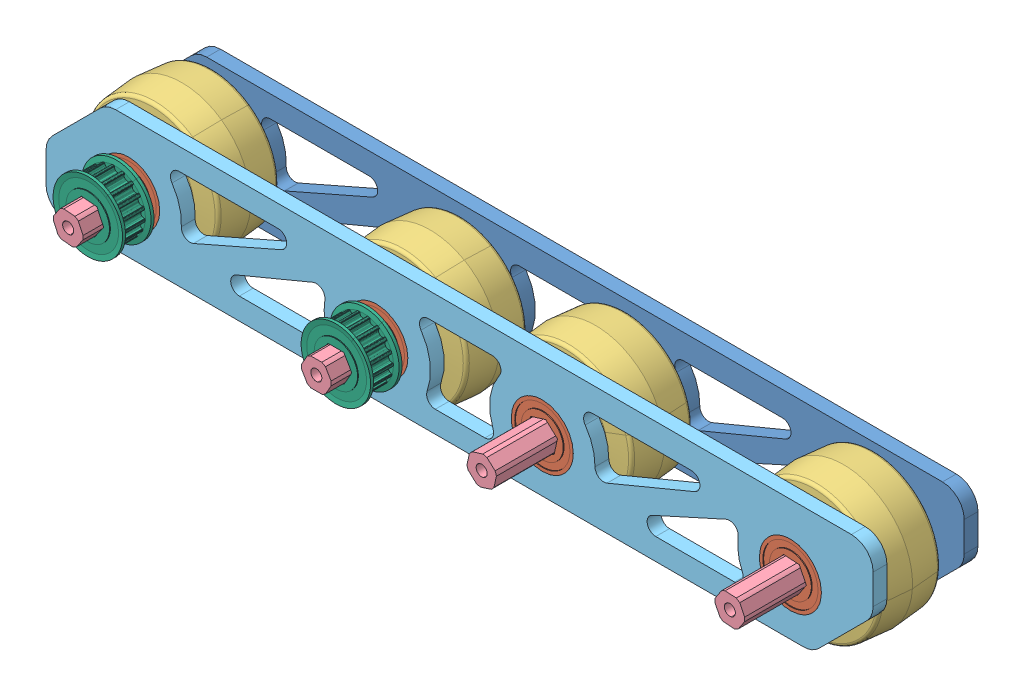
SolidWorks assembly 8WD, configuration Default. Lengths in mm.
Overall size (387.11 89.13 76.2).
20 component instances, 6 part files, 48 mates.
Components (placement in the parent):
- Part1-1: Part1 [Default] at (-97.1062 261.1901 376.3689) size (381 55.88 6.35)
- 0_500_Hex_ID_x_1_125_OD_x_0_313_WD_Flanged_Bearing_v2_217-3875 (1).step-1: 0_500_Hex_ID_x_1_125_OD_x_0_313_WD_Flanged_Bearing_v2_217-3875 (1).step [Default] at (-59.0062 286.9076 376.3689) x (0.574007 0.818851 0) z (0.818851 -0.574007 0) size (31.12 7.94 31.12)
- 0_500_Hex_ID_x_1_125_OD_x_0_313_WD_Flanged_Bearing_v2_217-3875 (1).step-2: 0_500_Hex_ID_x_1_125_OD_x_0_313_WD_Flanged_Bearing_v2_217-3875 (1).step [Default] at (55.2938 285.3201 376.3689) x (-0.99999 -0.004566 0) z (-0.004566 0.99999 0) size (31.12 7.94 31.12)
- 0_500_Hex_ID_x_1_125_OD_x_0_313_WD_Flanged_Bearing_v2_217-3875 (1).step-3: 0_500_Hex_ID_x_1_125_OD_x_0_313_WD_Flanged_Bearing_v2_217-3875 (1).step [Default] at (131.4938 285.3201 376.3689) x (0.953429 0.301619 0) z (0.301619 -0.953429 0) size (31.12 7.94 31.12)
- 0_500_Hex_ID_x_1_125_OD_x_0_313_WD_Flanged_Bearing_v2_217-3875 (1).step-4: 0_500_Hex_ID_x_1_125_OD_x_0_313_WD_Flanged_Bearing_v2_217-3875 (1).step [Default] at (245.7938 286.9076 376.3689) x (0.99802 -0.062897 0) z (-0.062897 -0.99802 0) size (31.12 7.94 31.12)
- Colson_Performa_2_5_x_1_25_1_2_Hex_bore_217-4046.step-1: Colson_Performa_2_5_x_1_25_1_2_Hex_bore_217-4046.step [Default] at (245.7924 286.9104 400.1814) x (0 0 1) z (-0.99802 0.062897 0) size (33.1 63.5 63.5)
- ThunderHex.5 2.25in-1: ThunderHex.5 2.25in [Default] at (245.784 286.8928 604.9689) x (0.55348 0.832862 0) z (0 0 1) size (13.74 12.75 76.2)
- ThunderHex.5 2.25in-2: ThunderHex.5 2.25in [Default] at (131.4769 285.3147 604.9689) x (0.215505 0.976503 0) z (0 0 1) size (13.74 12.75 76.2)
- Colson_Performa_2_5_x_1_25_1_2_Hex_bore_217-4046.step-2: Colson_Performa_2_5_x_1_25_1_2_Hex_bore_217-4046.step [Default] at (131.4629 285.3103 400.1814) x (0 0 1) z (-0.953429 -0.301619 0) size (33.1 63.5 63.5)
- ThunderHex.5 2.25in-3: ThunderHex.5 2.25in [Default] at (55.3116 285.3202 604.9689) x (-0.503949 0.863733 0) z (0 0 1) size (13.74 12.75 76.2)
- Colson_Performa_2_5_x_1_25_1_2_Hex_bore_217-4046.step-3: Colson_Performa_2_5_x_1_25_1_2_Hex_bore_217-4046.step [Default] at (55.3043 285.3074 400.1814) x (0 0 1) z (-0.49604 -0.8683 0) size (33.1 63.5 63.5)
- ThunderHex.5 2.25in-4: ThunderHex.5 2.25in [Default] at (-58.9885 286.906 604.9689) x (-0.422142 0.90653 0) z (0 0 1) size (13.74 12.75 76.2)
- Colson_Performa_2_5_x_1_25_1_2_Hex_bore_217-4046.step-4: Colson_Performa_2_5_x_1_25_1_2_Hex_bore_217-4046.step [Default] at (-58.9969 286.894 400.1814) x (0 0 1) z (-0.574007 -0.818851 0) size (33.1 63.5 63.5)
- Part2-1: Part2 [Default] at (-97.1062 261.1901 418.3186) size (381 55.88 6.35)
- 0_500_Hex_ID_x_1_125_OD_x_0_313_WD_Flanged_Bearing_v2_217-3875 (1).step-8: 0_500_Hex_ID_x_1_125_OD_x_0_313_WD_Flanged_Bearing_v2_217-3875 (1).step [Default] at (55.2938 285.3201 424.6686) x (-0.99999 -0.004566 0) z (0.004566 -0.99999 0) size (31.12 7.94 31.12)
- 0_500_Hex_ID_x_1_125_OD_x_0_313_WD_Flanged_Bearing_v2_217-3875 (1).step-6: 0_500_Hex_ID_x_1_125_OD_x_0_313_WD_Flanged_Bearing_v2_217-3875 (1).step [Default] at (131.4938 285.3201 424.6686) x (0.953429 0.301619 0) z (-0.301619 0.953429 0) size (31.12 7.94 31.12)
- 0_500_Hex_ID_x_1_125_OD_x_0_313_WD_Flanged_Bearing_v2_217-3875 (1).step-5: 0_500_Hex_ID_x_1_125_OD_x_0_313_WD_Flanged_Bearing_v2_217-3875 (1).step [Default] at (245.7938 286.9076 424.6686) x (0.99802 -0.062897 0) z (0.062897 0.99802 0) size (31.12 7.94 31.12)
- 0_500_Hex_ID_x_1_125_OD_x_0_313_WD_Flanged_Bearing_v2_217-3875 (1).step-7: 0_500_Hex_ID_x_1_125_OD_x_0_313_WD_Flanged_Bearing_v2_217-3875 (1).step [Default] at (-59.0062 286.9076 424.6686) x (0.574007 0.818851 0) z (-0.818851 0.574007 0) size (31.12 7.94 31.12)
- 18t_x_9mm_Wide_Double_Flange_Aluminum_Pulley_HTD_5mm_1_2_Hex_Bore_217-3225.step-1: 18t_x_9mm_Wide_Double_Flange_Aluminum_Pulley_HTD_5mm_1_2_Hex_Bore_217-3225.step [Default] at (-58.9592 286.9035 436.3044) x (0.574007 0.818851 0) z (0 0 1) size (32 32 14.5)
- 18t_x_9mm_Wide_Double_Flange_Aluminum_Pulley_HTD_5mm_1_2_Hex_Bore_217-3225.step-2: 18t_x_9mm_Wide_Double_Flange_Aluminum_Pulley_HTD_5mm_1_2_Hex_Bore_217-3225.step [Default] at (55.2971 285.2947 436.3044) x (0.49604 0.8683 0) z (0 0 1) size (32 32 14.5)
Mates (geometry in assembly coordinates):
- Concentric1: concentric: cylinder of Part1-1 through (-59.0062 286.9076 382.7189) axis (0 0 -1) radius 14.2875; cylinder of 0_500_Hex_ID_x_1_125_OD_x_0_313_WD_Flanged_Bearing_v2_217-3875 (1).step-1 through (-59.0062 286.9076 376.3689) axis (0 0 1) radius 14.2748
- Coincident1: coincident: plane of Part1-1 through (-97.1062 261.1901 382.7189) normal (0 0 1); plane of 0_500_Hex_ID_x_1_125_OD_x_0_313_WD_Flanged_Bearing_v2_217-3875 (1).step-1 through (-50.0761 299.6469 382.7189) normal (0 0 -1)
- Concentric2: concentric: cylinder of Part1-1 through (55.2938 285.3201 382.7189) axis (0 0 -1) radius 14.2875; cylinder of 0_500_Hex_ID_x_1_125_OD_x_0_313_WD_Flanged_Bearing_v2_217-3875 (1).step-2 through (55.2938 285.3201 376.3689) axis (0 0 1) radius 14.2748
- Concentric3: concentric: cylinder of Part1-1 through (131.4938 285.3201 382.7189) axis (0 0 -1) radius 14.2875; cylinder of 0_500_Hex_ID_x_1_125_OD_x_0_313_WD_Flanged_Bearing_v2_217-3875 (1).step-3 through (131.4938 285.3201 376.3689) axis (0 0 1) radius 14.2748
- Concentric4: concentric: cylinder of Part1-1 through (245.7938 286.9076 382.7189) axis (0 0 -1) radius 14.2875; cylinder of 0_500_Hex_ID_x_1_125_OD_x_0_313_WD_Flanged_Bearing_v2_217-3875 (1).step-4 through (245.7938 286.9076 376.3689) axis (0 0 1) radius 14.2748
- Coincident2: coincident: plane of Part1-1 through (-97.1062 261.1901 382.7189) normal (0 0 1); plane of 0_500_Hex_ID_x_1_125_OD_x_0_313_WD_Flanged_Bearing_v2_217-3875 (1).step-4 through (261.3205 285.9291 382.7189) normal (0 0 -1)
- Coincident3: coincident: plane of Part1-1 through (-97.1062 261.1901 382.7189) normal (0 0 1); plane of 0_500_Hex_ID_x_1_125_OD_x_0_313_WD_Flanged_Bearing_v2_217-3875 (1).step-3 through (146.3268 290.0125 382.7189) normal (0 0 -1)
- Coincident5: coincident: plane of Part1-1 through (-97.1062 261.1901 382.7189) normal (0 0 1); plane of 0_500_Hex_ID_x_1_125_OD_x_0_313_WD_Flanged_Bearing_v2_217-3875 (1).step-2 through (39.7365 285.2491 382.7189) normal (0 0 -1)
- Coincident7: coincident: plane of 0_500_Hex_ID_x_1_125_OD_x_0_313_WD_Flanged_Bearing_v2_217-3875 (1).step-4 through (241.7291 280.7911 376.3689) normal (0.062897 0.99802 0); plane of Colson_Performa_2_5_x_1_25_1_2_Hex_bore_217-4046.step-1 through (249.0512 280.3297 383.9318) normal (0.062897 0.99802 0)
- Coincident8: coincident: plane of 0_500_Hex_ID_x_1_125_OD_x_0_313_WD_Flanged_Bearing_v2_217-3875 (1).step-4 through (249.0585 280.3292 376.3689) normal (-0.832862 0.55348 0); plane of Colson_Performa_2_5_x_1_25_1_2_Hex_bore_217-4046.step-1 through (253.1208 286.4422 383.9318) normal (-0.832862 0.55348 0)
- Coincident9: coincident: plane of 0_500_Hex_ID_x_1_125_OD_x_0_313_WD_Flanged_Bearing_v2_217-3875 (1).step-4 through (249.8585 293.0241 376.3689) normal (-0.062897 -0.99802 0); plane of ThunderHex.5 2.25in-1 through (249.8585 293.0241 833.5689) normal (0.062897 0.99802 0)
- Coincident10: coincident: plane of 0_500_Hex_ID_x_1_125_OD_x_0_313_WD_Flanged_Bearing_v2_217-3875 (1).step-4 through (253.1232 286.4457 376.3689) normal (-0.895759 -0.44454 0); plane of ThunderHex.5 2.25in-1 through (253.1311 286.4298 833.5689) normal (0.895759 0.44454 0)
- Coincident11: coincident: plane of Part1-1 through (-97.1062 261.1901 376.3689) normal (0 0 -1); plane of ThunderHex.5 2.25in-1 through (245.784 286.8928 376.3689) normal (0 0 -1)
- Coincident12: coincident: plane of ThunderHex.5 2.25in-2 through (126.0445 290.283 833.5689) normal (-0.976503 0.215505 0); plane of Colson_Performa_2_5_x_1_25_1_2_Hex_bore_217-4046.step-2 through (124.4596 283.1015 383.9318) normal (0.976503 -0.215505 0)
- Coincident13: coincident: plane of ThunderHex.5 2.25in-2 through (124.458 283.0943 833.5689) normal (-0.674884 -0.737924 0); plane of Colson_Performa_2_5_x_1_25_1_2_Hex_bore_217-4046.step-2 through (129.8742 278.1409 383.9318) normal (0.674884 0.737924 0)
- Coincident15: coincident: plane of 0_500_Hex_ID_x_1_125_OD_x_0_313_WD_Flanged_Bearing_v2_217-3875 (1).step-3 through (138.4957 287.5352 376.3689) normal (-0.674884 -0.737924 0); plane of ThunderHex.5 2.25in-2 through (138.4957 287.5352 833.5689) normal (0.674884 0.737924 0)
- Coincident16: coincident: plane of 0_500_Hex_ID_x_1_125_OD_x_0_313_WD_Flanged_Bearing_v2_217-3875 (1).step-3 through (136.9131 280.3638 376.3689) normal (-0.976503 0.215505 0); plane of ThunderHex.5 2.25in-2 through (136.9092 280.3465 833.5689) normal (0.976503 -0.215505 0)
- Coincident17: coincident: plane of Part1-1 through (-97.1062 261.1901 376.3689) normal (0 0 -1); plane of ThunderHex.5 2.25in-2 through (131.4769 285.3147 376.3689) normal (0 0 -1)
- Coincident18: coincident: plane of ThunderHex.5 2.25in-3 through (47.95 285.2866 833.5689) normal (-0.863733 -0.503949 0); plane of Colson_Performa_2_5_x_1_25_1_2_Hex_bore_217-4046.step-3 through (51.6562 278.9344 383.9318) normal (0.863733 0.503949 0)
- Coincident19: coincident: plane of ThunderHex.5 2.25in-3 through (51.6599 278.928 833.5689) normal (0.004566 -0.99999 0); plane of Colson_Performa_2_5_x_1_25_1_2_Hex_bore_217-4046.step-3 through (58.9995 278.9616 383.9318) normal (-0.004566 0.99999 0)
- Coincident20: coincident: plane of ThunderHex.5 2.25in-4 through (-66.3218 287.5515 833.5689) normal (-0.90653 -0.422142 0); plane of Colson_Performa_2_5_x_1_25_1_2_Hex_bore_217-4046.step-4 through (-63.2172 280.8846 383.9318) normal (0.90653 0.422142 0)
- Coincident21: coincident: plane of ThunderHex.5 2.25in-4 through (-63.2141 280.8779 833.5689) normal (-0.087679 -0.996149 0); plane of Colson_Performa_2_5_x_1_25_1_2_Hex_bore_217-4046.step-4 through (-55.9027 280.2344 383.9318) normal (0.087679 0.996149 0)
- Coincident22: coincident: plane of 0_500_Hex_ID_x_1_125_OD_x_0_313_WD_Flanged_Bearing_v2_217-3875 (1).step-2 through (51.5929 291.6633 376.3689) normal (0.8683 -0.49604 0); plane of ThunderHex.5 2.25in-3 through (51.6017 291.6787 833.5689) normal (-0.8683 0.49604 0)
- Coincident23: coincident: plane of 0_500_Hex_ID_x_1_125_OD_x_0_313_WD_Flanged_Bearing_v2_217-3875 (1).step-2 through (47.95 285.2866 376.3689) normal (0.863733 0.503949 0); plane of ThunderHex.5 2.25in-3 through (47.95 285.2866 833.5689) normal (-0.863733 -0.503949 0)
- Coincident24: coincident: plane of 0_500_Hex_ID_x_1_125_OD_x_0_313_WD_Flanged_Bearing_v2_217-3875 (1).step-1 through (-62.1063 293.5651 376.3689) normal (0.818851 -0.574007 0); plane of ThunderHex.5 2.25in-4 through (-62.0961 293.5796 833.5689) normal (-0.818851 0.574007 0)
- Coincident25: coincident: plane of 0_500_Hex_ID_x_1_125_OD_x_0_313_WD_Flanged_Bearing_v2_217-3875 (1).step-1 through (-66.3218 287.5515 376.3689) normal (0.90653 0.422142 0); plane of ThunderHex.5 2.25in-4 through (-66.3218 287.5515 833.5689) normal (-0.90653 -0.422142 0)
- Coincident26: coincident: plane of Part1-1 through (-97.1062 261.1901 376.3689) normal (0 0 -1); plane of ThunderHex.5 2.25in-3 through (55.3116 285.3202 376.3689) normal (0 0 -1)
- Coincident27: coincident: plane of Part1-1 through (-97.1062 261.1901 376.3689) normal (0 0 -1); plane of ThunderHex.5 2.25in-4 through (-58.9885 286.906 376.3689) normal (0 0 -1)
- Coincident28: coincident: plane of Colson_Performa_2_5_x_1_25_1_2_Hex_bore_217-4046.step-3 through (40.0865 294.0011 416.0564) normal (0 0 1); plane of Colson_Performa_2_5_x_1_25_1_2_Hex_bore_217-4046.step-2 through (126.1767 302.0201 416.0564) normal (0 0 1)
- Coincident29: coincident: plane of Colson_Performa_2_5_x_1_25_1_2_Hex_bore_217-4046.step-3 through (40.0865 294.0011 416.0564) normal (0 0 1); plane of Colson_Performa_2_5_x_1_25_1_2_Hex_bore_217-4046.step-4 through (-73.3481 296.9541 416.0564) normal (0 0 1)
- Coincident30: coincident: plane of Colson_Performa_2_5_x_1_25_1_2_Hex_bore_217-4046.step-1 through (246.8948 304.4017 416.0564) normal (0 0 1); plane of Colson_Performa_2_5_x_1_25_1_2_Hex_bore_217-4046.step-2 through (126.1767 302.0201 416.0564) normal (0 0 1)
- Coincident31: coincident: plane of 0_500_Hex_ID_x_1_125_OD_x_0_313_WD_Flanged_Bearing_v2_217-3875 (1).step-1 through (-51.7163 297.307 384.3064) normal (0 0 1); plane of Colson_Performa_2_5_x_1_25_1_2_Hex_bore_217-4046.step-4 through (-73.3481 296.9541 384.3064) normal (0 0 -1)
- Coincident33: coincident: plane of ThunderHex.5 2.25in-4 through (-51.6551 286.2606 833.5689) normal (0.90653 0.422142 0); plane of 18t_x_9mm_Wide_Double_Flange_Aluminum_Pulley_HTD_5mm_1_2_Hex_Bore_217-3225.step-1 through (-53.2028 289.5841 443.5544) normal (-0.90653 -0.422142 0)
- Coincident34: coincident: plane of ThunderHex.5 2.25in-4 through (-55.8808 280.2325 833.5689) normal (0.818851 -0.574007 0); plane of 18t_x_9mm_Wide_Double_Flange_Aluminum_Pulley_HTD_5mm_1_2_Hex_Bore_217-3225.step-1 through (-53.7595 283.2585 443.5544) normal (-0.818851 0.574007 0)
- Coincident35: coincident: plane of ThunderHex.5 2.25in-3 through (51.6599 278.928 833.5689) normal (0.004566 -0.99999 0); plane of 18t_x_9mm_Wide_Double_Flange_Aluminum_Pulley_HTD_5mm_1_2_Hex_Bore_217-3225.step-2 through (55.3261 278.9448 443.5544) normal (-0.004566 0.99999 0)
- Coincident36: coincident: plane of ThunderHex.5 2.25in-3 through (47.95 285.2866 833.5689) normal (-0.863733 -0.503949 0); plane of 18t_x_9mm_Wide_Double_Flange_Aluminum_Pulley_HTD_5mm_1_2_Hex_Bore_217-3225.step-2 through (49.8124 282.0946 443.5544) normal (0.863733 0.503949 0)
- Coincident37: coincident: plane of 18t_x_9mm_Wide_Double_Flange_Aluminum_Pulley_HTD_5mm_1_2_Hex_Bore_217-3225.step-1 through (-58.9592 286.9035 443.5544) normal (0 0 1); plane of 18t_x_9mm_Wide_Double_Flange_Aluminum_Pulley_HTD_5mm_1_2_Hex_Bore_217-3225.step-2 through (55.2971 285.2947 443.5544) normal (0 0 1)
- Concentric9: concentric: cylinder of Part2-1 through (-59.0062 286.9076 424.6686) axis (0 0 -1) radius 14.2875; cylinder of 0_500_Hex_ID_x_1_125_OD_x_0_313_WD_Flanged_Bearing_v2_217-3875 (1).step-7 through (-59.0062 286.9076 424.6686) axis (0 0 -1) radius 14.2748
- Coincident42: coincident: plane of Part2-1 through (-97.1062 261.1901 418.3186) normal (0 0 -1); plane of 0_500_Hex_ID_x_1_125_OD_x_0_313_WD_Flanged_Bearing_v2_217-3875 (1).step-7 through (-50.0761 299.6469 418.3186) normal (0 0 1)
- Concentric10: concentric: cylinder of Part2-1 through (55.2938 285.3201 424.6686) axis (0 0 -1) radius 14.2875; cylinder of 0_500_Hex_ID_x_1_125_OD_x_0_313_WD_Flanged_Bearing_v2_217-3875 (1).step-8 through (55.2938 285.3201 424.6686) axis (0 0 -1) radius 14.2748
- Concentric11: concentric: cylinder of Part2-1 through (131.4938 285.3201 424.6686) axis (0 0 -1) radius 14.2875; cylinder of 0_500_Hex_ID_x_1_125_OD_x_0_313_WD_Flanged_Bearing_v2_217-3875 (1).step-6 through (131.4938 285.3201 424.6686) axis (0 0 -1) radius 14.2748
- Concentric12: concentric: cylinder of Part2-1 through (245.7938 286.9076 424.6686) axis (0 0 -1) radius 14.2875; cylinder of 0_500_Hex_ID_x_1_125_OD_x_0_313_WD_Flanged_Bearing_v2_217-3875 (1).step-5 through (245.7938 286.9076 424.6686) axis (0 0 -1) radius 14.2748
- Coincident43: coincident: plane of Part2-1 through (-97.1062 261.1901 418.3186) normal (0 0 -1); plane of 0_500_Hex_ID_x_1_125_OD_x_0_313_WD_Flanged_Bearing_v2_217-3875 (1).step-5 through (261.3205 285.9291 418.3186) normal (0 0 1)
- Coincident44: coincident: plane of Part2-1 through (-97.1062 261.1901 418.3186) normal (0 0 -1); plane of 0_500_Hex_ID_x_1_125_OD_x_0_313_WD_Flanged_Bearing_v2_217-3875 (1).step-6 through (146.3268 290.0125 418.3186) normal (0 0 1)
- Coincident45: coincident: plane of Part2-1 through (-97.1062 261.1901 418.3186) normal (0 0 -1); plane of 0_500_Hex_ID_x_1_125_OD_x_0_313_WD_Flanged_Bearing_v2_217-3875 (1).step-8 through (39.7365 285.2491 418.3186) normal (0 0 1)
- Coincident46: coincident: plane of Part1-1 through (-97.1062 317.0701 382.7189) normal (0 1 0); plane of Part2-1 through (-97.1062 317.0701 424.6686) normal (0 1 0)
- Coincident47: coincident: plane of Part1-1 through (-97.1062 261.1901 382.7189) normal (-1 0 0); plane of Part2-1 through (-97.1062 261.1901 424.6686) normal (-1 0 0)
- Coincident48: coincident: plane of Colson_Performa_2_5_x_1_25_1_2_Hex_bore_217-4046.step-4 through (-58.9969 286.894 416.7311) normal (0 0 1); plane of 0_500_Hex_ID_x_1_125_OD_x_0_313_WD_Flanged_Bearing_v2_217-3875 (1).step-7 through (-51.7163 297.307 416.7311) normal (0 0 -1)
